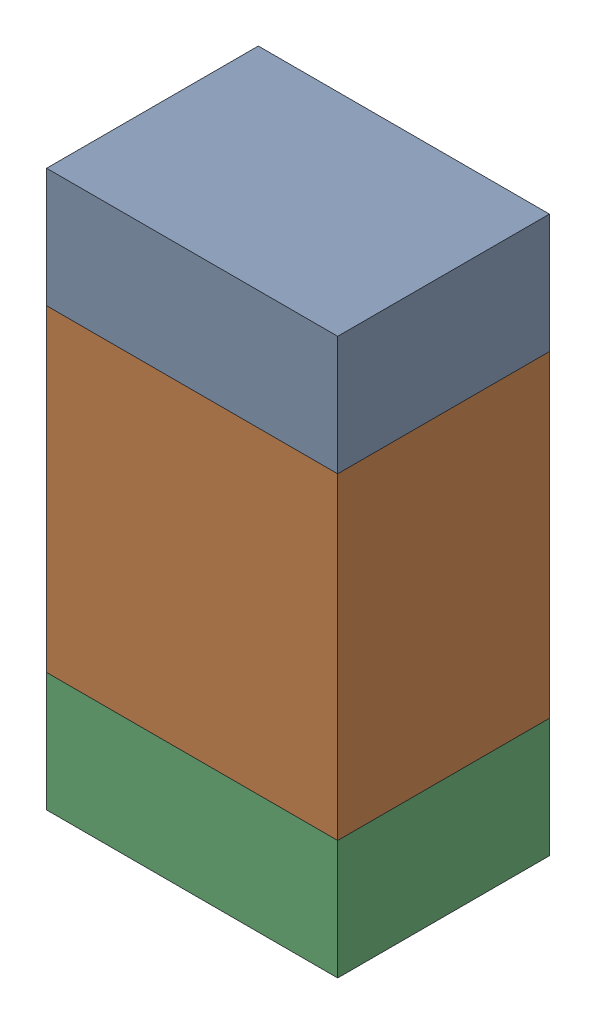
SolidWorks assembly R307_2PCB, configuration Default. Lengths in mm.
Overall size (0.55 1.05 0.4).
6 component instances, 2 part files, 0 mates.
Components (placement in the parent):
- 846483288-1: 846483288 [Default] at (136.3001 96.5124 0) size (0.55 0.22 0.4)
  - Extruded_12-1: Extruded_12 [Default] at origin size (0.55 0.22 0.4)
- 846483424-1: 846483424 [Default] at (136.3001 96.0999 0) size (0.55 0.6 0.4)
  - Extruded_13-1: Extruded_13 [Default] at origin size (0.55 0.6 0.4)
- 846483288-2: 846483288 [Default] at (136.3001 95.6874 0) size (0.55 0.22 0.4)
  - Extruded_12-1: Extruded_12 [Default] at origin size (0.55 0.22 0.4)
